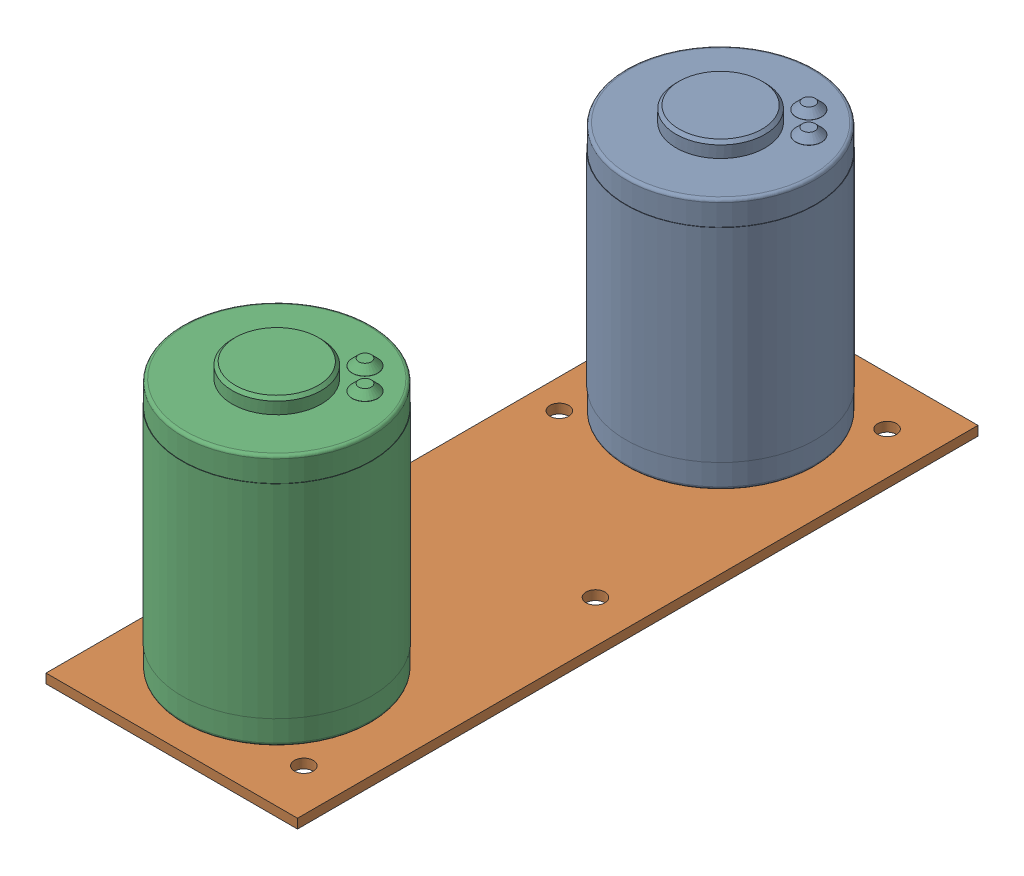
SolidWorks assembly Intake_Top_Plate_Assembly, configuration Default. Lengths in mm.
Overall size (85 125.82 230).
3 component instances, 2 part files, 0 mates.
Components (placement in the parent):
- Mini_Cim-1: Mini_Cim [Default] at (24.7712 115 -75) x (0 1 0) z (-1 0 0) size (125.82 64.01 64.01)
- Intake_Top_Plate-1: Intake_Top_Plate [Default] at (29.2712 115 0) x (0 -1 0) z (0 0 1) size (3.17 85 230)
- Mini_Cim-2: Mini_Cim [Default] at (24.7712 115 75) x (0 1 0) z (-1 0 0) size (125.82 64.01 64.01)
